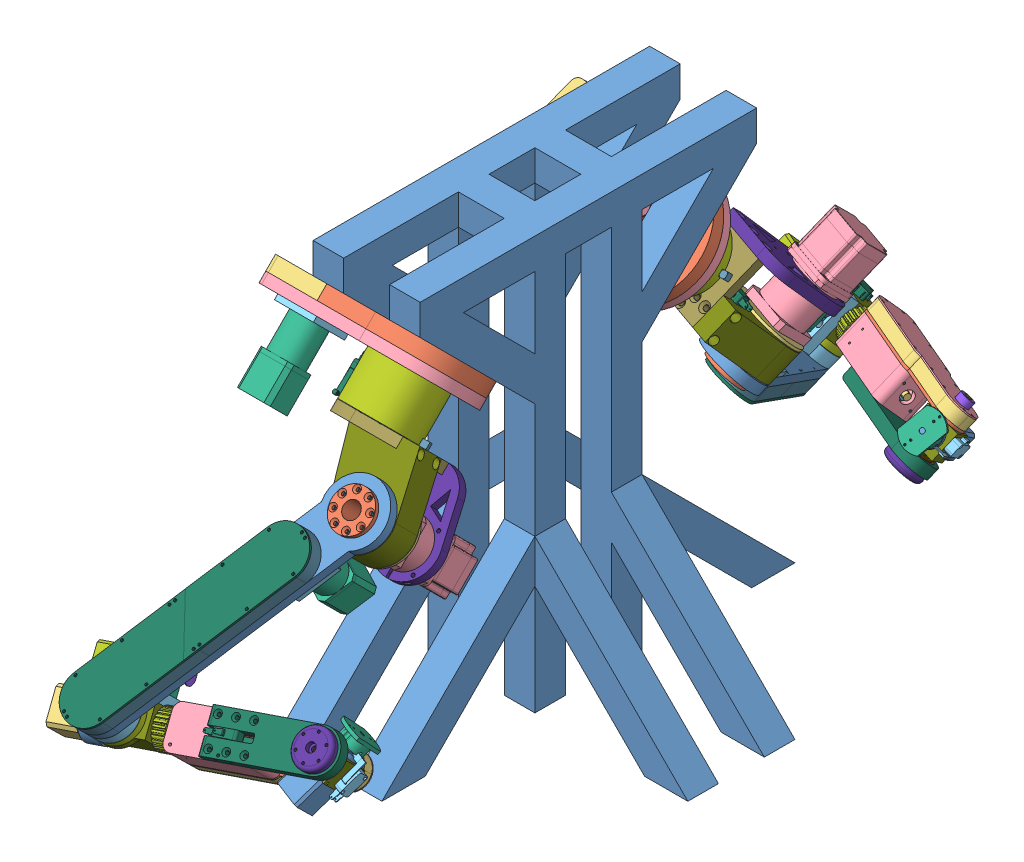
SolidWorks assembly 装配体2, configuration 默认. Lengths in mm.
Overall size (540 568.46 1164.83).
167 component instances, 61 part files, 2 mates.
Components (placement in the parent):
- body_support3-1: body_support3 [默认] at (-107.6803 -474.2368 840) size (540 540 540)
- AR2 Robot-1: AR2 Robot [Default] at (-128.1127 63.5014 972.2906) x (-0.025853 -0.70687 -0.70687) z (0 -0.707107 0.707107) size (202.33 345.86 499.96)
  - J1 base support spacer part 1-1: J1 base support spacer part 1 [Default] at (22.3846 43.8071 138.2023) size (150 163.98 18)
  - J1 base support spacer part 2-1: J1 base support spacer part 2 [Default] at (22.3846 43.8071 138.2023) size (115.01 90.53 18)
  - J1 Base Plate-1: J1 Base Plate [Default] at (22.3846 91.3071 156.2023) size (150 245 12.7)
  - J1 & J3 Motor Mount-1: J1 & J3 Motor Mount [Default] at (22.3846 -32.6929 168.9023) size (60 50 6.35)
  - 17HS15-1684S-HG50-1: 17HS15-1684S-HG50 [Default] at (22.3846 -32.6929 223.5523) size (42.3 42.3 112.8)
  - J1 Turret Housing-1: J1 Turret Housing [Default] at (22.3846 91.3071 224.9023) x (0 1 0) z (0 0 -1) size (88.9 88.9 60)
  - J1 timing drive pulley-1: J1 timing drive pulley [Default] at (22.3846 -32.6929 141.9013) x (0.998528 0.05424 0) z (0.05424 -0.998528 0) size (28 25 28)
  - J1 bearing outer-1: J1 bearing outer [Default] at (22.3846 91.3071 219.9023) x (0.366401 0.930457 0) z (-0.930457 0.366401 0) size (75 15.5 75)
  - J1 bearing outer-2: J1 bearing outer [Default] at (22.3846 91.3071 169.9023) x (0.999226 -0.039335 0) z (-0.039335 -0.999226 0) size (75 15.5 75)
  - J1 bearing inner-1: J1 bearing inner [Default] at (22.3846 91.3071 225.4756) x (0.21691 0.976192 0) z (-0.976192 0.21691 0) size (71.6 20 71.6)
  - J1 bearing inner-2: J1 bearing inner [Default] at (22.3846 91.3071 165.345) x (0.788003 0.615672 0) z (0.615672 -0.788003 0) size (71.6 20 71.6)
  - J1 Spindle-1: J1 Spindle [Default] at (22.3846 91.3071 230.4103) x (0.795489 -0.605968 0) z (0 0 -1) size (50 50 83)
  - J1 Turret Platform-1: J1 Turret Platform [Default] at (22.3846 91.3071 225.4103) x (0.999953 -0.00971 0) z (0 0 1) size (88.9 104.45 13.08)
  - J1 timing pulley-1: J1 timing pulley [Default] at (22.3846 91.3071 148.2513) x (0 0 1) z (0.134012 -0.99098 0) size (12.7 96.5 96.5)
  - 92635A314_SQUARE HEAD EXTENDED POINT SET SCREW-1: 92635A314_SQUARE HEAD EXTENDED POINT SET SCREW [92635A314] at (34.2576 140.3585 237.9103) x (-0.955272 0.295727 0) z (0 0 -1) size (8.33 8.21 30.75)
  - micro switch-1: micro switch [Valor predeterminado] at (22.4346 42.5829 198.1926) x (0 1 0) z (0 0 1) size (10.3 28.24 49.65)
  - J2 Turret Housing-1: J2 Turret Housing [Default] at (19.089 45.4301 436.03) x (0 0 1) z (-0.999953 0.00971 0) size (120.57 102.2 41.6)
  - J2 Motor Support-1: J2 Motor Support [Default] at (79.0823 44.4493 449.5798) x (0 0 1) z (-0.999953 0.00971 0) size (120.54 102.2 12.7)
  - 30206-1: 30206 [Default] at (11.5602 216.8333 260.6239) x (-0.009358 -0.96366 -0.266969) z (-0.002592 -0.266957 0.963705) size (65.5 17.98 65.5)
  - 30206-2: 30206 [Default] at (-12.4111 178.2286 233.8653) x (0.005755 0.592672 0.805423) z (-0.007821 -0.805385 0.5927) size (65.5 17.98 65.5)
  - J2 Arm-1: J2 Arm [Default] at (-22.7033 155.8935 307.9857) x (-0.008654 -0.89121 -0.453508) z (-0.999953 0.00971 0) size (76 373 12.7)
  - micro switch-2: micro switch [Valor predeterminado] at (-18.8536 37.4191 515.1548) x (0.999953 -0.00971 0) z (-0.008141 -0.838355 0.545065) size (10.3 28.24 49.65)
  - J2 Drive Spindle-1: J2 Drive Spindle [Default] at (20.1346 155.4775 307.9857) x (-0.008654 -0.89121 -0.453508) z (-0.999953 0.00971 0) size (50.8 50.8 61.54)
  - J2 Tension Ring-1: J2 Tension Ring [Default] at (21.0396 155.4687 307.9857) x (-0.009697 -0.998554 0.052877) z (0.999953 -0.00971 0) size (94.3 76 3.17)
  - micro switch-3: micro switch [Valor predeterminado] at (25.0171 140.9821 250.7197) x (0.999953 -0.00971 0) z (-0.00971 -0.999953 0) size (10.3 28.24 49.65)
  - 23HS22-2804S-HG50-1: 23HS22-2804S-HG50 [Default] at (82.6952 154.9259 307.9797) x (0.00971 0.999953 0) z (0 0 1) size (57 150.65 57)
  - J1 & J3 Motor Mount-2: J1 & J3 Motor Mount [Default] at (-23.0073 124.5927 369.5021) x (0.008654 0.89121 0.453508) z (0.999953 -0.00971 0) size (60 50 6.35)
  - 17HS15-1684S-HG50-2: 17HS15-1684S-HG50 [Default] at (31.6401 124.0621 369.5021) x (0.004404 0.453487 -0.891252) z (0.999953 -0.00971 0) size (42.3 42.3 112.8)
  - J3 Bearing Cup-1: J3 Bearing Cup [Default] at (-9.0472 17.4344 579.8176) x (0.008045 0.828458 0.559993) z (-0.999953 0.00971 0) size (60 60 15)
  - 30204 bearing-1: 30204 bearing [6677K54] at (-19.0467 17.5315 579.8176) x (0.003716 0.382666 -0.923879) z (0.999953 -0.00971 0) size (47 47 15.14)
  - J3 Spindle-1: J3 Spindle [Default] at (-9.0472 17.4344 579.8176) x (0.009307 0.958433 -0.285164) z (0.999953 -0.00971 0) size (60 60 50)
  - 5909K180_THRUST NEEDLE-ROLLER BRNG-1: 5909K180_THRUST NEEDLE-ROLLER BRNG [5909K18] at (-7.0473 17.415 579.8176) x (0.006928 0.713409 0.700713) z (-0.006804 -0.70068 0.713443) size (52 2 52)
  - 5909K630_THRUST NEEDLE-ROLLER BRNG-1: 5909K630_THRUST NEEDLE-ROLLER BRNG [5909K63] at (28.0358 56.6986 568.0293) x (-0.009307 -0.958433 0.285164) z (0.303367 0.26903 0.914107) size (3.2 39.69 39.69)
  - 5909K780_THRUST NEEDLE-ROLLER BRNG-1: 5909K780_THRUST NEEDLE-ROLLER BRNG [5909K78] at (-9.0472 17.4344 579.8176) x (0.999953 -0.00971 0) z (0.000045 0.004685 0.999989) size (1 52 52)
  - 5909K780_THRUST NEEDLE-ROLLER BRNG-2: 5909K780_THRUST NEEDLE-ROLLER BRNG [5909K78] at (-6.0473 17.4053 579.8176) x (0.999953 -0.00971 0) z (0.000043 0.004399 0.99999) size (1 52 52)
  - J3 spindle retainer-1: J3 spindle retainer [Default] at (-26.522 -31.3786 761.9544) x (0.002769 0.285151 0.958479) z (-0.999953 0.00971 0) size (31.75 31.75 2)
  - 5909K490_THRUST NEEDLE-ROLLER BRNG-1: 5909K490_THRUST NEEDLE-ROLLER BRNG [5909K49] at (27.4067 -8.0864 587.3049) x (-0.009307 -0.958433 0.285164) z (0.172118 0.279385 0.944627) size (0.81 39.69 39.69)
  - 1439K211_METRIC FULLY KEYED STEEL DRIVE SHAFT-1: 1439K211_METRIC FULLY KEYED STEEL DRIVE SHAFT [1439K211] at (-16.5468 17.5072 579.8176) x (-0.009307 -0.958433 0.285164) z (-0.999953 0.00971 0) size (8 7.87 35)
  - J2 arm cover spacer-1: J2 arm cover spacer [Default] at (-37.1017 -18.9384 323.0929) x (-0.008654 -0.89121 -0.453508) z (-0.999953 0.00971 0) size (60 145.49 19.05)
  - J2 arm cover spacer-2: J2 arm cover spacer [Default] at (-35.3729 159.0904 630.6831) x (0.008654 0.89121 0.453508) z (-0.999953 0.00971 0) size (60 145.49 19.05)
  - J2 side cover half -1: J2 side cover half  [Default] at (-58.4278 73.736 415.9133) x (0.008654 0.89121 0.453508) z (0.999953 -0.00971 0) size (60 162.81 3.17)
  - J2 side cover half -2: J2 side cover half  [Default] at (-58.4947 66.8476 537.8627) x (-0.008654 -0.89121 -0.453508) z (0.999953 -0.00971 0) size (60 162.81 3.17)
  - J4 Turret Housing-1: J4 Turret Housing [Default] at (0.9524 17.3373 579.8176) x (0.009307 0.958433 -0.285164) z (0.999953 -0.00971 0) size (58.8 60 45.4)
  - 5905K137_STL NEEDLE-ROLLER BRNG-2: 5905K137_STL NEEDLE-ROLLER BRNG [5905K137] at (27.8618 38.7782 573.3611) x (0.254471 0.273518 0.927595) z (-0.009307 -0.958433 0.285164) size (31.75 31.75 25.4)
  - J4 Main Shaft-1: J4 Main Shaft [Default] at (28.355 89.5657 558.2503) x (-0.999873 0.012613 0.009759) z (-0.009307 -0.958433 0.285164) size (25.4 25.4 116.3)
  - 5905K137_STL NEEDLE-ROLLER BRNG-1: 5905K137_STL NEEDLE-ROLLER BRNG [5905K137] at (27.551 6.7666 582.8856) x (0.991141 -0.046627 -0.124363) z (0.009307 0.958433 -0.285164) size (31.75 31.75 25.4)
  - J5 motor mount-1: J5 motor mount [Default] at (27.4308 -5.6068 586.5671) x (-0.999873 0.012613 0.009759) z (-0.009307 -0.958433 0.285164) size (52 52 20)
  - 5909K490_THRUST NEEDLE-ROLLER BRNG-2: 5909K490_THRUST NEEDLE-ROLLER BRNG [5909K49] at (27.4252 -6.1846 586.739) x (0.009307 0.958433 -0.285164) z (-0.878097 0.144266 0.456215) size (0.81 39.69 39.69)
  - 5909K360_THRUST NEEDLE-ROLLER BRNG-1: 5909K360_THRUST NEEDLE-ROLLER BRNG [5909K36] at (27.416 -7.1355 587.0219) x (0.437217 0.252572 0.863162) z (-0.899308 0.132712 0.416692) size (39.69 1.98 39.69)
  - 5909K490_THRUST NEEDLE-ROLLER BRNG-3: 5909K490_THRUST NEEDLE-ROLLER BRNG [5909K49] at (27.9876 51.7294 569.5078) x (-0.009307 -0.958433 0.285164) z (-0.202783 0.28106 0.938021) size (0.81 39.69 39.69)
  - 5909K360_THRUST NEEDLE-ROLLER BRNG-2: 5909K360_THRUST NEEDLE-ROLLER BRNG [5909K36] at (27.9968 52.6803 569.2248) x (0.998571 -0.023915 -0.047786) z (0.05262 0.284312 0.957287) size (39.69 1.98 39.69)
  - 17LS13-0404E-200H-1: 17LS13-0404E-200H [Default] at (26.9282 -57.3622 601.966) x (0.999873 -0.012613 -0.009759) z (0.009307 0.958433 -0.285164) size (42.3 42.3 236)
  - micro switch-4: micro switch [Valor predeterminado] at (51.3984 21.8369 575.1379) x (-0.999953 0.00971 0) z (-0.005226 -0.538152 0.842831) size (10.3 28.24 49.65)
  - J5 Housing-1: J5 Housing [Default] at (8.4486 72.983 589.5353) x (0.009307 0.958433 -0.285164) z (0.999873 -0.012613 -0.009759) size (107.7 50 40)
  - J4 motor mount - limit arm-1: J4 motor mount - limit arm [Default] at (46.5936 41.9599 540.1302) x (-0.999953 0.00971 0) z (-0.009307 -0.958433 0.285164) size (68 12.19 53.8)
  - nema 11 bracket-1: nema 11 bracket [Default] at (41.5482 37.3098 541.5282) x (-0.009307 -0.958433 0.285164) z (-0.999953 0.00971 0) size (40 40 30)
  - 11HS20-0674S-PG5-1: 11HS20-0674S-PG5 [Default] at (26.2041 1.9466 528.076) x (0.999953 -0.00971 0) z (-0.009307 -0.958433 0.285164) size (30.3 30.3 98.7)
  - J4 timing drive pulley-1: J4 timing drive pulley [Default] at (26.648 47.6639 514.4737) x (-0.165849 0.282707 0.94476) z (0.986107 0.038501 0.161586) size (21 20 21)
  - 6677K520_STL TAPERED-ROLLER BRNG-1: 6677K520_STL TAPERED-ROLLER BRNG [6677K52] at (4.2264 230.777 516.58) x (-0.013651 -0.993291 -0.114832) z (-0.999873 0.012613 0.009759) size (40 40 13.16)
  - 3mm rod-1: 3mm rod [Default] at (20.3071 172.9321 548.173) x (0.898948 -0.13292 -0.417403) z (-0.009307 -0.958433 0.285164) size (3 3 105)
  - 3mm rod-2: 3mm rod [Default] at (36.965 64.0885 551.1036) x (0.443693 0.251608 0.860133) z (0.009307 0.958433 -0.285164) size (3 3 105)
  - J5 Belt Carrier-1: J5 Belt Carrier [Default] at (38.5014 118.2441 548.7149) x (-0.995382 0.036126 0.088932) z (0.009307 0.958433 -0.285164) size (50.4 38.49 20.9)
  - J5 Belt Carrier Clamp-1: J5 Belt Carrier Clamp [Default] at (38.3643 129.2512 515.5701) x (-0.997523 -0.010986 -0.069481) z (-0.009307 -0.958433 0.285164) size (15.26 4.44 10)
  - J5 Idler Tension Block-1: J5 Idler Tension Block [Default] at (43.0941 83.6757 538.9353) x (-0.009307 -0.958433 0.285164) z (0.999873 -0.012613 -0.009759) size (15 40 5)
  - J5 Bearing Post-1: J5 Bearing Post [Default] at (48.2827 82.1251 560.1938) x (0.015948 0.791024 0.611577) z (0.999873 -0.012613 -0.009759) size (18.92 18.92 16.94)
  - J6 main bearing arm-1: J6 main bearing arm [Default] at (-5.1029 119.1644 575.984) x (0.009307 0.958433 -0.285164) z (0.999873 -0.012613 -0.009759) size (150 50 14)
  - micro switch-5: micro switch [Valor predeterminado] at (0.4979 134.3321 545.4175) x (0.01295 0.285037 0.958429) z (0.009307 0.958433 -0.285164) size (10.3 28.24 49.65)
  - J6 housing single piece-1: J6 housing single piece [Default] at (48.8777 191.7396 542.6928) x (-0.999873 0.012613 0.009759) z (-0.005075 0.328473 -0.9445) size (83.08 41 30.8)
  - J6 bearing cap-1: J6 bearing cap [Default] at (-4.4701 230.8867 516.6648) x (0.015119 0.555024 0.831697) z (-0.999873 0.012613 0.009759) size (46 46 10)
  - 5909K360_THRUST NEEDLE-ROLLER BRNG-3: 5909K360_THRUST NEEDLE-ROLLER BRNG [5909K36] at (-6.0773 230.907 516.6805) x (0.000889 0.655076 -0.755563) z (0.015923 0.755458 0.655003) size (39.69 1.98 39.69)
  - 5909K490_THRUST NEEDLE-ROLLER BRNG-4: 5909K490_THRUST NEEDLE-ROLLER BRNG [5909K49] at (-5.0852 230.8945 516.6709) x (0.999873 -0.012613 -0.009759) z (0.015948 0.792537 0.609615) size (0.81 39.69 39.69)
  - 5909K630_THRUST NEEDLE-ROLLER BRNG-2: 5909K630_THRUST NEEDLE-ROLLER BRNG [5909K63] at (-10.2693 230.9599 516.7215) x (0.999873 -0.012613 -0.009759) z (0.008673 -0.083448 0.996474) size (3.2 39.69 39.69)
  - J1 timing drive pulley-2: J1 timing drive pulley [Default] at (52.7144 230.1653 516.1067) x (0.004223 -0.380663 0.924704) z (0.015378 0.924628 0.380561) size (28 25 28)
  - 5905K760_STL NEEDLE-ROLLER BRNG-1: 5905K760_STL NEEDLE-ROLLER BRNG [5905K76] at (57.6485 82.007 560.1024) x (0.010168 0.032823 0.999409) z (-0.999873 0.012613 0.009759) size (22 22 12)
  - 14HS13-0804S-PG19-1: 14HS13-0804S-PG19 [Default] at (31.57 213.3877 565.3352) x (-0.015119 -0.944429 -0.328367) z (-0.005075 0.328473 -0.9445) size (35 35 87.8)
  - J5 side cover-1: J5 side cover [Default] at (50.0578 -32.289 564.6055) x (-0.003228 -0.759342 0.650684) z (-0.999873 0.012613 0.009759) size (184.01 109.77 3.17)
  - J5 side cover spacer-1: J5 side cover spacer [Default] at (65.0559 -32.4782 564.4591) x (-0.003228 -0.759342 0.650684) z (-0.999873 0.012613 0.009759) size (182.25 90.14 15)
  - J5 side cover spacer-2: J5 side cover spacer [Default] at (50.7924 -16.1211 618.9696) x (-0.013773 -0.991449 -0.129769) z (0.999873 -0.012613 -0.009759) size (182.25 90.14 15)
  - J5 side cover cap-1: J5 side cover cap [Default] at (67.2958 26.4304 555.1422) x (-0.003228 -0.759342 0.650684) z (-0.999873 0.012613 0.009759) size (184.01 109.77 1.59)
  - modified micro switch-1: modified micro switch [Valor predeterminado] at (37.2465 254.1199 525.5794) x (-0.015119 -0.944429 -0.328367) z (-0.005075 0.328473 -0.9445) size (18.14 22.93 48.86)
  - J6 gripper mount-1: J6 gripper mount [Default] at (31.2038 237.087 497.1895) x (0.992264 0.118813 0.035989) z (-0.005075 0.328473 -0.9445) size (48 32 16)
  - J4 timing hub-2: J4 timing hub [Default] at (27.9799 50.9408 569.7424) x (0.01295 0.285037 0.958429) z (0.009307 0.958433 -0.285164) size (44.7 44.7 15)
- AR2 Robot-2: AR2 Robot [Default] at (-126.4333 44.7862 866.4246) x (0.297224 0.675151 -0.675151) z (0 -0.707107 -0.707107) size (202.33 345.86 499.96)
  - J1 base support spacer part 1-1: J1 base support spacer part 1 [Default] at (22.3846 43.8071 138.2023) size (150 163.98 18)
  - J1 base support spacer part 2-1: J1 base support spacer part 2 [Default] at (22.3846 43.8071 138.2023) size (115.01 90.53 18)
  - J1 Base Plate-1: J1 Base Plate [Default] at (22.3846 91.3071 156.2023) size (150 245 12.7)
  - J1 & J3 Motor Mount-1: J1 & J3 Motor Mount [Default] at (22.3846 -32.6929 168.9023) size (60 50 6.35)
  - 17HS15-1684S-HG50-1: 17HS15-1684S-HG50 [Default] at (22.3846 -32.6929 223.5523) size (42.3 42.3 112.8)
  - J1 Turret Housing-1: J1 Turret Housing [Default] at (22.3846 91.3071 224.9023) x (0 1 0) z (0 0 -1) size (88.9 88.9 60)
  - J1 timing drive pulley-1: J1 timing drive pulley [Default] at (22.3846 -32.6929 141.9013) x (0.998528 0.05424 0) z (0.05424 -0.998528 0) size (28 25 28)
  - J1 bearing outer-1: J1 bearing outer [Default] at (22.3846 91.3071 219.9023) x (0.366401 0.930457 0) z (-0.930457 0.366401 0) size (75 15.5 75)
  - J1 bearing outer-2: J1 bearing outer [Default] at (22.3846 91.3071 169.9023) x (0.999226 -0.039335 0) z (-0.039335 -0.999226 0) size (75 15.5 75)
  - J1 bearing inner-1: J1 bearing inner [Default] at (22.3846 91.3071 225.4756) x (0.21691 0.976192 0) z (-0.976192 0.21691 0) size (71.6 20 71.6)
  - J1 bearing inner-2: J1 bearing inner [Default] at (22.3846 91.3071 165.345) x (0.788003 0.615672 0) z (0.615672 -0.788003 0) size (71.6 20 71.6)
  - J1 Spindle-1: J1 Spindle [Default] at (22.3846 91.3071 230.4103) x (0.795489 -0.605968 0) z (0 0 -1) size (50 50 83)
  - J1 Turret Platform-1: J1 Turret Platform [Default] at (22.3846 91.3071 225.4103) x (0.999953 -0.00971 0) z (0 0 1) size (88.9 104.45 13.08)
  - J1 timing pulley-1: J1 timing pulley [Default] at (22.3846 91.3071 148.2513) x (0 0 1) z (0.134012 -0.99098 0) size (12.7 96.5 96.5)
  - 92635A314_SQUARE HEAD EXTENDED POINT SET SCREW-1: 92635A314_SQUARE HEAD EXTENDED POINT SET SCREW [92635A314] at (34.2576 140.3585 237.9103) x (-0.955272 0.295727 0) z (0 0 -1) size (8.33 8.21 30.75)
  - micro switch-1: micro switch [Valor predeterminado] at (22.4346 42.5829 198.1926) x (0 1 0) z (0 0 1) size (10.3 28.24 49.65)
  - J2 Turret Housing-1: J2 Turret Housing [Default] at (19.089 45.4301 436.03) x (0 0 1) z (-0.999953 0.00971 0) size (120.57 102.2 41.6)
  - J2 Motor Support-1: J2 Motor Support [Default] at (79.0823 44.4493 449.5798) x (0 0 1) z (-0.999953 0.00971 0) size (120.54 102.2 12.7)
  - 30206-1: 30206 [Default] at (11.5602 216.8333 260.6239) x (-0.009358 -0.96366 -0.266969) z (-0.002592 -0.266957 0.963705) size (65.5 17.98 65.5)
  - 30206-2: 30206 [Default] at (-12.4111 178.2286 233.8653) x (0.005755 0.592672 0.805423) z (-0.007821 -0.805385 0.5927) size (65.5 17.98 65.5)
  - J2 Arm-1: J2 Arm [Default] at (-22.7033 155.8935 307.9857) x (-0.008654 -0.89121 -0.453508) z (-0.999953 0.00971 0) size (76 373 12.7)
  - micro switch-2: micro switch [Valor predeterminado] at (-18.8536 37.4191 515.1548) x (0.999953 -0.00971 0) z (-0.008141 -0.838355 0.545065) size (10.3 28.24 49.65)
  - J2 Drive Spindle-1: J2 Drive Spindle [Default] at (20.1346 155.4775 307.9857) x (-0.008654 -0.89121 -0.453508) z (-0.999953 0.00971 0) size (50.8 50.8 61.54)
  - J2 Tension Ring-1: J2 Tension Ring [Default] at (21.0396 155.4687 307.9857) x (-0.009697 -0.998554 0.052877) z (0.999953 -0.00971 0) size (94.3 76 3.17)
  - micro switch-3: micro switch [Valor predeterminado] at (25.0171 140.9821 250.7197) x (0.999953 -0.00971 0) z (-0.00971 -0.999953 0) size (10.3 28.24 49.65)
  - 23HS22-2804S-HG50-1: 23HS22-2804S-HG50 [Default] at (82.6952 154.9259 307.9797) x (0.00971 0.999953 0) z (0 0 1) size (57 150.65 57)
  - J1 & J3 Motor Mount-2: J1 & J3 Motor Mount [Default] at (-23.0073 124.5927 369.5021) x (0.008654 0.89121 0.453508) z (0.999953 -0.00971 0) size (60 50 6.35)
  - 17HS15-1684S-HG50-2: 17HS15-1684S-HG50 [Default] at (31.6401 124.0621 369.5021) x (0.004404 0.453487 -0.891252) z (0.999953 -0.00971 0) size (42.3 42.3 112.8)
  - J3 Bearing Cup-1: J3 Bearing Cup [Default] at (-9.0472 17.4344 579.8176) x (0.008045 0.828458 0.559993) z (-0.999953 0.00971 0) size (60 60 15)
  - 30204 bearing-1: 30204 bearing [6677K54] at (-19.0467 17.5315 579.8176) x (0.003716 0.382666 -0.923879) z (0.999953 -0.00971 0) size (47 47 15.14)
  - J3 Spindle-1: J3 Spindle [Default] at (-9.0472 17.4344 579.8176) x (0.009307 0.958433 -0.285164) z (0.999953 -0.00971 0) size (60 60 50)
  - 5909K180_THRUST NEEDLE-ROLLER BRNG-1: 5909K180_THRUST NEEDLE-ROLLER BRNG [5909K18] at (-7.0473 17.415 579.8176) x (0.006928 0.713409 0.700713) z (-0.006804 -0.70068 0.713443) size (52 2 52)
  - 5909K630_THRUST NEEDLE-ROLLER BRNG-1: 5909K630_THRUST NEEDLE-ROLLER BRNG [5909K63] at (28.0358 56.6986 568.0293) x (-0.009307 -0.958433 0.285164) z (0.303367 0.26903 0.914107) size (3.2 39.69 39.69)
  - 5909K780_THRUST NEEDLE-ROLLER BRNG-1: 5909K780_THRUST NEEDLE-ROLLER BRNG [5909K78] at (-9.0472 17.4344 579.8176) x (0.999953 -0.00971 0) z (0.000045 0.004685 0.999989) size (1 52 52)
  - 5909K780_THRUST NEEDLE-ROLLER BRNG-2: 5909K780_THRUST NEEDLE-ROLLER BRNG [5909K78] at (-6.0473 17.4053 579.8176) x (0.999953 -0.00971 0) z (0.000043 0.004399 0.99999) size (1 52 52)
  - J3 spindle retainer-1: J3 spindle retainer [Default] at (-26.522 -31.3786 761.9544) x (0.002769 0.285151 0.958479) z (-0.999953 0.00971 0) size (31.75 31.75 2)
  - 5909K490_THRUST NEEDLE-ROLLER BRNG-1: 5909K490_THRUST NEEDLE-ROLLER BRNG [5909K49] at (27.4067 -8.0864 587.3049) x (-0.009307 -0.958433 0.285164) z (0.172118 0.279385 0.944627) size (0.81 39.69 39.69)
  - 1439K211_METRIC FULLY KEYED STEEL DRIVE SHAFT-1: 1439K211_METRIC FULLY KEYED STEEL DRIVE SHAFT [1439K211] at (-16.5468 17.5072 579.8176) x (-0.009307 -0.958433 0.285164) z (-0.999953 0.00971 0) size (8 7.87 35)
  - J2 arm cover spacer-1: J2 arm cover spacer [Default] at (-37.1017 -18.9384 323.0929) x (-0.008654 -0.89121 -0.453508) z (-0.999953 0.00971 0) size (60 145.49 19.05)
  - J2 arm cover spacer-2: J2 arm cover spacer [Default] at (-35.3729 159.0904 630.6831) x (0.008654 0.89121 0.453508) z (-0.999953 0.00971 0) size (60 145.49 19.05)
  - J2 side cover half -1: J2 side cover half  [Default] at (-58.4278 73.736 415.9133) x (0.008654 0.89121 0.453508) z (0.999953 -0.00971 0) size (60 162.81 3.17)
  - J2 side cover half -2: J2 side cover half  [Default] at (-58.4947 66.8476 537.8627) x (-0.008654 -0.89121 -0.453508) z (0.999953 -0.00971 0) size (60 162.81 3.17)
  - J4 Turret Housing-1: J4 Turret Housing [Default] at (0.9524 17.3373 579.8176) x (0.009307 0.958433 -0.285164) z (0.999953 -0.00971 0) size (58.8 60 45.4)
  - 5905K137_STL NEEDLE-ROLLER BRNG-2: 5905K137_STL NEEDLE-ROLLER BRNG [5905K137] at (27.8618 38.7782 573.3611) x (0.254471 0.273518 0.927595) z (-0.009307 -0.958433 0.285164) size (31.75 31.75 25.4)
  - J4 Main Shaft-1: J4 Main Shaft [Default] at (28.355 89.5657 558.2503) x (-0.999873 0.012613 0.009759) z (-0.009307 -0.958433 0.285164) size (25.4 25.4 116.3)
  - 5905K137_STL NEEDLE-ROLLER BRNG-1: 5905K137_STL NEEDLE-ROLLER BRNG [5905K137] at (27.551 6.7666 582.8856) x (0.991141 -0.046627 -0.124363) z (0.009307 0.958433 -0.285164) size (31.75 31.75 25.4)
  - J5 motor mount-1: J5 motor mount [Default] at (27.4308 -5.6068 586.5671) x (-0.999873 0.012613 0.009759) z (-0.009307 -0.958433 0.285164) size (52 52 20)
  - 5909K490_THRUST NEEDLE-ROLLER BRNG-2: 5909K490_THRUST NEEDLE-ROLLER BRNG [5909K49] at (27.4252 -6.1846 586.739) x (0.009307 0.958433 -0.285164) z (-0.878097 0.144266 0.456215) size (0.81 39.69 39.69)
  - 5909K360_THRUST NEEDLE-ROLLER BRNG-1: 5909K360_THRUST NEEDLE-ROLLER BRNG [5909K36] at (27.416 -7.1355 587.0219) x (0.437217 0.252572 0.863162) z (-0.899308 0.132712 0.416692) size (39.69 1.98 39.69)
  - 5909K490_THRUST NEEDLE-ROLLER BRNG-3: 5909K490_THRUST NEEDLE-ROLLER BRNG [5909K49] at (27.9876 51.7294 569.5078) x (-0.009307 -0.958433 0.285164) z (-0.202783 0.28106 0.938021) size (0.81 39.69 39.69)
  - 5909K360_THRUST NEEDLE-ROLLER BRNG-2: 5909K360_THRUST NEEDLE-ROLLER BRNG [5909K36] at (27.9968 52.6803 569.2248) x (0.998571 -0.023915 -0.047786) z (0.05262 0.284312 0.957287) size (39.69 1.98 39.69)
  - 17LS13-0404E-200H-1: 17LS13-0404E-200H [Default] at (26.9282 -57.3622 601.966) x (0.999873 -0.012613 -0.009759) z (0.009307 0.958433 -0.285164) size (42.3 42.3 236)
  - micro switch-4: micro switch [Valor predeterminado] at (51.3984 21.8369 575.1379) x (-0.999953 0.00971 0) z (-0.005226 -0.538152 0.842831) size (10.3 28.24 49.65)
  - J5 Housing-1: J5 Housing [Default] at (8.4486 72.983 589.5353) x (0.009307 0.958433 -0.285164) z (0.999873 -0.012613 -0.009759) size (107.7 50 40)
  - J4 motor mount - limit arm-1: J4 motor mount - limit arm [Default] at (46.5936 41.9599 540.1302) x (-0.999953 0.00971 0) z (-0.009307 -0.958433 0.285164) size (68 12.19 53.8)
  - nema 11 bracket-1: nema 11 bracket [Default] at (41.5482 37.3098 541.5282) x (-0.009307 -0.958433 0.285164) z (-0.999953 0.00971 0) size (40 40 30)
  - 11HS20-0674S-PG5-1: 11HS20-0674S-PG5 [Default] at (26.2041 1.9466 528.076) x (0.999953 -0.00971 0) z (-0.009307 -0.958433 0.285164) size (30.3 30.3 98.7)
  - J4 timing drive pulley-1: J4 timing drive pulley [Default] at (26.648 47.6639 514.4737) x (-0.165849 0.282707 0.94476) z (0.986107 0.038501 0.161586) size (21 20 21)
  - 6677K520_STL TAPERED-ROLLER BRNG-1: 6677K520_STL TAPERED-ROLLER BRNG [6677K52] at (4.2264 230.777 516.58) x (-0.013651 -0.993291 -0.114832) z (-0.999873 0.012613 0.009759) size (40 40 13.16)
  - 3mm rod-1: 3mm rod [Default] at (20.3071 172.9321 548.173) x (0.898948 -0.13292 -0.417403) z (-0.009307 -0.958433 0.285164) size (3 3 105)
  - 3mm rod-2: 3mm rod [Default] at (36.965 64.0885 551.1036) x (0.443693 0.251608 0.860133) z (0.009307 0.958433 -0.285164) size (3 3 105)
  - J5 Belt Carrier-1: J5 Belt Carrier [Default] at (38.5014 118.2441 548.7149) x (-0.995382 0.036126 0.088932) z (0.009307 0.958433 -0.285164) size (50.4 38.49 20.9)
  - J5 Belt Carrier Clamp-1: J5 Belt Carrier Clamp [Default] at (38.3643 129.2512 515.5701) x (-0.997523 -0.010986 -0.069481) z (-0.009307 -0.958433 0.285164) size (15.26 4.44 10)
  - J5 Idler Tension Block-1: J5 Idler Tension Block [Default] at (43.0941 83.6757 538.9353) x (-0.009307 -0.958433 0.285164) z (0.999873 -0.012613 -0.009759) size (15 40 5)
  - J5 Bearing Post-1: J5 Bearing Post [Default] at (48.2827 82.1251 560.1938) x (0.015948 0.791024 0.611577) z (0.999873 -0.012613 -0.009759) size (18.92 18.92 16.94)
  - J6 main bearing arm-1: J6 main bearing arm [Default] at (-5.1029 119.1644 575.984) x (0.009307 0.958433 -0.285164) z (0.999873 -0.012613 -0.009759) size (150 50 14)
  - micro switch-5: micro switch [Valor predeterminado] at (0.4979 134.3321 545.4175) x (0.01295 0.285037 0.958429) z (0.009307 0.958433 -0.285164) size (10.3 28.24 49.65)
  - J6 housing single piece-1: J6 housing single piece [Default] at (48.8777 191.7396 542.6928) x (-0.999873 0.012613 0.009759) z (-0.005075 0.328473 -0.9445) size (83.08 41 30.8)
  - J6 bearing cap-1: J6 bearing cap [Default] at (-4.4701 230.8867 516.6648) x (0.015119 0.555024 0.831697) z (-0.999873 0.012613 0.009759) size (46 46 10)
  - 5909K360_THRUST NEEDLE-ROLLER BRNG-3: 5909K360_THRUST NEEDLE-ROLLER BRNG [5909K36] at (-6.0773 230.907 516.6805) x (0.000889 0.655076 -0.755563) z (0.015923 0.755458 0.655003) size (39.69 1.98 39.69)
  - 5909K490_THRUST NEEDLE-ROLLER BRNG-4: 5909K490_THRUST NEEDLE-ROLLER BRNG [5909K49] at (-5.0852 230.8945 516.6709) x (0.999873 -0.012613 -0.009759) z (0.015948 0.792537 0.609615) size (0.81 39.69 39.69)
  - 5909K630_THRUST NEEDLE-ROLLER BRNG-2: 5909K630_THRUST NEEDLE-ROLLER BRNG [5909K63] at (-10.2693 230.9599 516.7215) x (0.999873 -0.012613 -0.009759) z (0.008673 -0.083448 0.996474) size (3.2 39.69 39.69)
  - J1 timing drive pulley-2: J1 timing drive pulley [Default] at (52.7144 230.1653 516.1067) x (0.004223 -0.380663 0.924704) z (0.015378 0.924628 0.380561) size (28 25 28)
  - 5905K760_STL NEEDLE-ROLLER BRNG-1: 5905K760_STL NEEDLE-ROLLER BRNG [5905K76] at (57.6485 82.007 560.1024) x (0.010168 0.032823 0.999409) z (-0.999873 0.012613 0.009759) size (22 22 12)
  - 14HS13-0804S-PG19-1: 14HS13-0804S-PG19 [Default] at (31.57 213.3877 565.3352) x (-0.015119 -0.944429 -0.328367) z (-0.005075 0.328473 -0.9445) size (35 35 87.8)
  - J5 side cover-1: J5 side cover [Default] at (50.0578 -32.289 564.6055) x (-0.003228 -0.759342 0.650684) z (-0.999873 0.012613 0.009759) size (184.01 109.77 3.17)
  - J5 side cover spacer-1: J5 side cover spacer [Default] at (65.0559 -32.4782 564.4591) x (-0.003228 -0.759342 0.650684) z (-0.999873 0.012613 0.009759) size (182.25 90.14 15)
  - J5 side cover spacer-2: J5 side cover spacer [Default] at (50.7924 -16.1211 618.9696) x (-0.013773 -0.991449 -0.129769) z (0.999873 -0.012613 -0.009759) size (182.25 90.14 15)
  - J5 side cover cap-1: J5 side cover cap [Default] at (67.2958 26.4304 555.1422) x (-0.003228 -0.759342 0.650684) z (-0.999873 0.012613 0.009759) size (184.01 109.77 1.59)
  - modified micro switch-1: modified micro switch [Valor predeterminado] at (37.2465 254.1199 525.5794) x (-0.015119 -0.944429 -0.328367) z (-0.005075 0.328473 -0.9445) size (18.14 22.93 48.86)
  - J6 gripper mount-1: J6 gripper mount [Default] at (31.2038 237.087 497.1895) x (0.992264 0.118813 0.035989) z (-0.005075 0.328473 -0.9445) size (48 32 16)
  - J4 timing hub-2: J4 timing hub [Default] at (27.9799 50.9408 569.7424) x (0.01295 0.285037 0.958429) z (0.009307 0.958433 -0.285164) size (44.7 44.7 15)
Mates (geometry in assembly coordinates):
- 重合1: coincident anti-aligned: plane of body_support3-1 through (-7.6803 25.7632 1130) normal (0 -0.707107 0.707107); plane of AR2 Robot-1/J1 base support spacer part 2-1 through (-196.5359 -26.2194 1078.0174) normal (0 0.707107 -0.707107)
- 重合2: coincident anti-aligned: plane of body_support3-1 through (-67.6803 25.7632 690) normal (0 -0.707107 -0.707107); plane of AR2 Robot-2/J1 base support spacer part 2-1 through (-194.8589 -44.9449 760.7081) normal (0 0.707107 0.707107)
